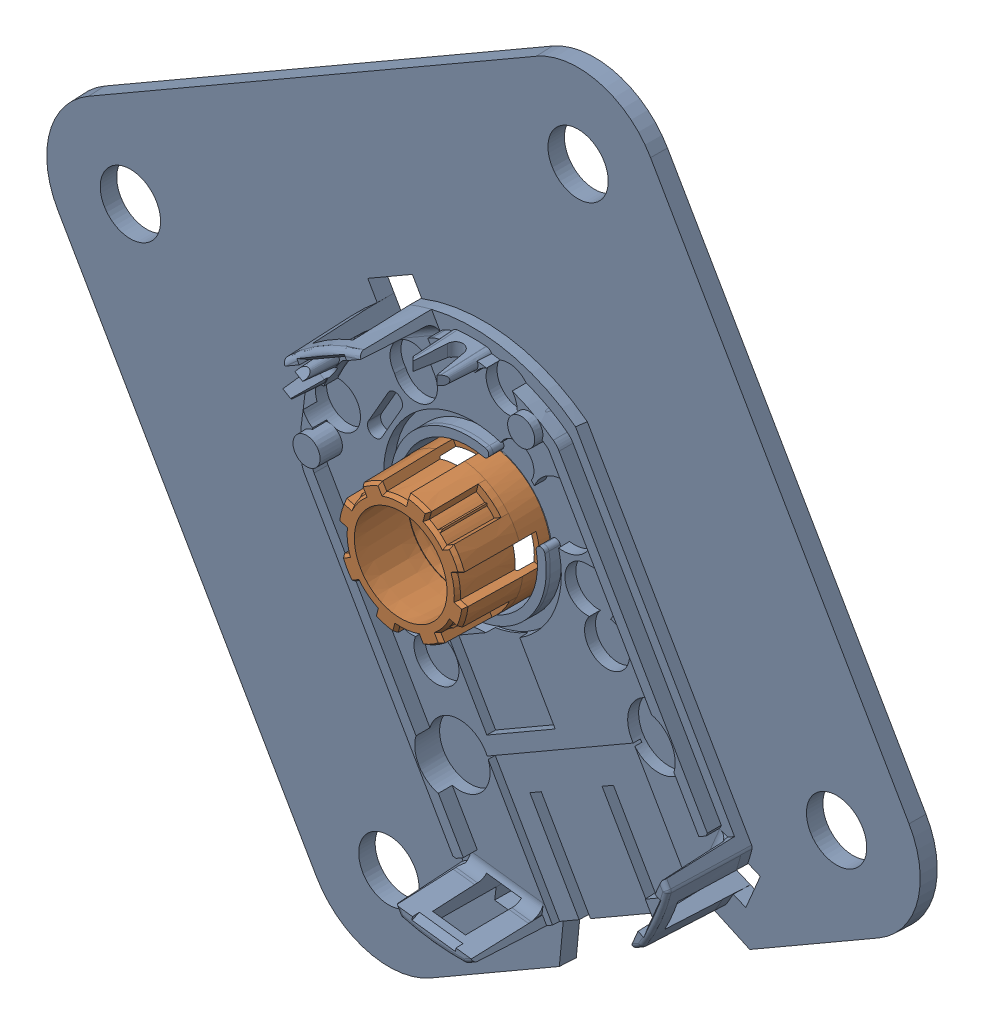
SolidWorks assembly amt102-v _1_, configuration Default. Lengths in mm.
Overall size (85.38 85.38 9.09).
2 component instances, 2 part files, 0 mates.
Components (placement in the parent):
- amt102-v_01-1: amt102-v_01 [Default] at (0.0989 0.2528 32.9636) x (0.866025 0.5 0) z (0 0 1) size (62.5 62.5 9.09)
- amt102-v_06-1: amt102-v_06 [Default] at (0.0989 0.2528 32.9636) x (0.866025 0.5 0) z (0 0 1) size (11.92 11.92 7.8)
